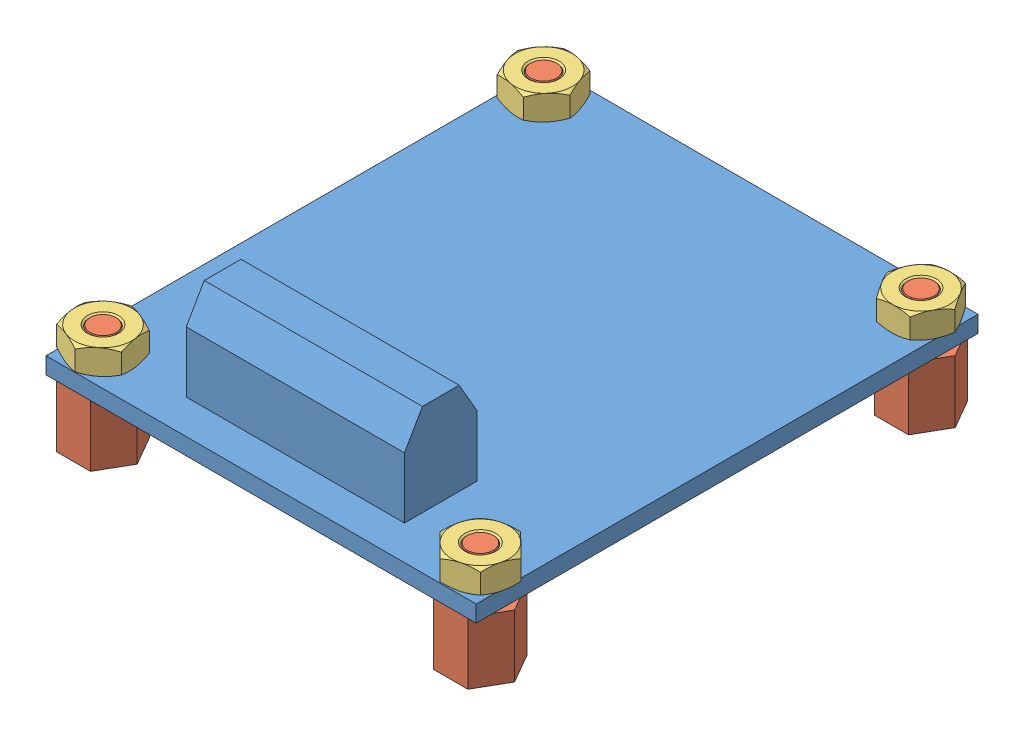
SolidWorks assembly motor-pcb-with-spacers, configuration Default. Lengths in mm.
Overall size (44.62 16.45 50.96).
9 component instances, 3 part files, 20 mates.
Components (placement in the parent):
- motor-pcb-1: motor-pcb [Default] at origin size (41.4 10.45 48.3)
- pcb-spacer-6mm-1: pcb-spacer-6mm [Default] at (-18.16 -6 21.205) x (0.5 0 0.866025) z (-0.866025 0 0.5) size (6.58 9.95 5.7)
- hex nut style 1_am-1: hex nut style 1_am [B18.2.4.1M - Hex nut, Style 1,  M3 x 0.5 --D-C] at (-18.16 4 21.205) x (0.989555 0 -0.144154) z (0 1 0) size (5.5 6.35 2.4)
- pcb-spacer-6mm-2: pcb-spacer-6mm [Default] at (-18.16 -6 -21.205) x (0.5 0 0.866025) z (-0.866025 0 0.5) size (6.58 9.95 5.7)
- hex nut style 1_am-2: hex nut style 1_am [B18.2.4.1M - Hex nut, Style 1,  M3 x 0.5 --D-C] at (-18.16 4 -21.205) x (0.944658 0 -0.328058) z (0 1 0) size (5.5 6.35 2.4)
- pcb-spacer-6mm-3: pcb-spacer-6mm [Default] at (18.16 -6 -21.205) size (6.58 9.95 5.7)
- hex nut style 1_am-3: hex nut style 1_am [B18.2.4.1M - Hex nut, Style 1,  M3 x 0.5 --D-C] at (18.16 4 -21.205) x (0.851726 0 -0.523987) z (0 1 0) size (5.5 6.35 2.4)
- pcb-spacer-6mm-4: pcb-spacer-6mm [Default] at (18.16 -6 21.205) size (6.58 9.95 5.7)
- hex nut style 1_am-4: hex nut style 1_am [B18.2.4.1M - Hex nut, Style 1,  M3 x 0.5 --D-C] at (18.16 4 21.205) x (0.705152 0 -0.709057) z (0 1 0) size (5.5 6.35 2.4)
Mates (geometry in assembly coordinates):
- Concentric1: concentric aligned: cylinder of motor-pcb-1 through (-18.16 1.6 21.205) axis (0 -1 0) radius 1.5; cylinder of pcb-spacer-6mm-1 through (-18.16 3.95 21.205) axis (0 -1 0) radius 1.45
- Coincident1: coincident anti-aligned: plane of motor-pcb-1 through (0 0 0) normal (0 -1 0); plane of pcb-spacer-6mm-1 through (-18.16 0 21.205) normal (0 1 0)
- Concentric2: concentric anti-aligned: cylinder of pcb-spacer-6mm-1 through (-18.16 3.95 21.205) axis (0 -1 0) radius 1.45; cylinder of hex nut style 1_am-1 through (-18.16 1.6 21.205) axis (0 1 0) radius 1.25
- Coincident2: coincident anti-aligned: plane of motor-pcb-1 through (0 1.6 0) normal (0 1 0); plane of hex nut style 1_am-1 through (-18.6178 1.6 18.0627) normal (0 -1 0)
- Concentric3: concentric anti-aligned: cylinder of pcb-spacer-6mm-2 through (-18.16 3.95 -21.205) axis (0 -1 0) radius 1.45; cylinder of hex nut style 1_am-2 through (-18.16 1.6 -21.205) axis (0 1 0) radius 1.25
- Concentric4: concentric aligned: cylinder of motor-pcb-1 through (-18.16 1.6 -21.205) axis (0 -1 0) radius 1.5; cylinder of pcb-spacer-6mm-2 through (-18.16 3.95 -21.205) axis (0 -1 0) radius 1.45
- Coincident3: coincident anti-aligned: plane of motor-pcb-1 through (0 0 0) normal (0 -1 0); plane of pcb-spacer-6mm-2 through (-18.16 0 -21.205) normal (0 1 0)
- Coincident4: coincident anti-aligned: plane of motor-pcb-1 through (0 1.6 0) normal (0 1 0); plane of hex nut style 1_am-2 through (-19.2017 1.6 -24.2047) normal (0 -1 0)
- Concentric5: concentric anti-aligned: cylinder of pcb-spacer-6mm-3 through (18.16 3.95 -21.205) axis (0 -1 0) radius 1.45; cylinder of hex nut style 1_am-3 through (18.16 1.6 -21.205) axis (0 1 0) radius 1.25
- Coincident5: coincident anti-aligned: plane of motor-pcb-1 through (0 0 0) normal (0 -1 0); plane of pcb-spacer-6mm-3 through (18.16 0 -21.205) normal (0 1 0)
- Coincident6: coincident anti-aligned: plane of motor-pcb-1 through (0 1.6 0) normal (0 1 0); plane of hex nut style 1_am-3 through (16.4961 1.6 -23.9096) normal (0 -1 0)
- Concentric6: concentric aligned: cylinder of motor-pcb-1 through (18.16 1.6 -21.205) axis (0 -1 0) radius 1.5; cylinder of pcb-spacer-6mm-3 through (18.16 3.95 -21.205) axis (0 -1 0) radius 1.45
- Concentric7: concentric anti-aligned: cylinder of pcb-spacer-6mm-4 through (18.16 3.95 21.205) axis (0 -1 0) radius 1.45; cylinder of hex nut style 1_am-4 through (18.16 1.6 21.205) axis (0 1 0) radius 1.25
- Coincident7: coincident anti-aligned: plane of motor-pcb-1 through (0 0 0) normal (0 -1 0); plane of pcb-spacer-6mm-4 through (18.16 0 21.205) normal (0 1 0)
- Coincident8: coincident anti-aligned: plane of motor-pcb-1 through (0 1.6 0) normal (0 1 0); plane of hex nut style 1_am-4 through (15.9084 1.6 18.9658) normal (0 -1 0)
- Concentric8: concentric aligned: cylinder of motor-pcb-1 through (18.16 1.6 21.205) axis (0 -1 0) radius 1.5; cylinder of pcb-spacer-6mm-4 through (18.16 3.95 21.205) axis (0 -1 0) radius 1.45
- Parallel1: parallel aligned: plane of motor-pcb-1 through (20.7 1.6 24.15) normal (0 0 1); plane of pcb-spacer-6mm-4 through (16.5146 -1 24.055) normal (0 0 1)
- Parallel2: parallel aligned: plane of motor-pcb-1 through (20.7 1.6 24.15) normal (0 0 1); plane of pcb-spacer-6mm-1 through (-19.8054 -1 24.055) normal (0 0 1)
- Parallel3: parallel aligned: plane of motor-pcb-1 through (20.7 1.6 -24.15) normal (0 0 -1); plane of pcb-spacer-6mm-3 through (19.8054 -1 -24.055) normal (0 0 -1)
- Parallel4: parallel aligned: plane of motor-pcb-1 through (20.7 1.6 -24.15) normal (0 0 -1); plane of pcb-spacer-6mm-2 through (-16.5146 -1 -24.055) normal (0 0 -1)
